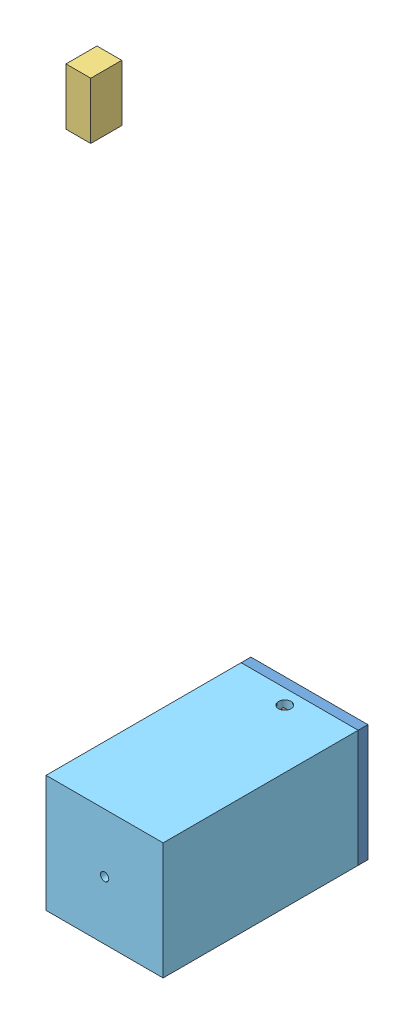
SolidWorks assembly Tongue assembly, configuration Default. Lengths in mm.
Overall size (482.24 379.28 414.44).
5 component instances, 5 part files, 9 mates.
Components (placement in the parent):
- Front plate-1: Front plate [Default] at (336.2892 -25.1944 124.8895) size (120 120 10)
- Tongue-1: Tongue [Default] at (336.2892 59.8056 131.8895) x (1 0 0) z (0 1 0) size (30 16.5 46)
- Solenoid-1: Solenoid [Default] at (-73.2537 296.0844 -68.6464) size (25.4 58 31.8)
- Part1-1: Part1 [Default] at (357.7174 122.6882 129.8895) size (40 65 4.5)
- Box-1: Box [Default] at (336.2892 34.8056 319.8895) x (1 0 0) z (0 -1 0) size (120 200 120)
Mates (geometry in assembly coordinates):
- Coincident1: coincident anti-aligned: plane of Front plate-1 through (276.2892 94.8056 129.8895) normal (0 0 1); plane of Tongue-1 through (336.2892 59.8056 129.8895) normal (0 0 -1)
- Coincident4: coincident anti-aligned: plane of Front plate-1 through (276.2892 94.8056 129.8895) normal (0 0 1); plane of Part1-1 through (357.7174 122.6882 129.8895) normal (0 0 -1)
- Concentric2: concentric anti-aligned: circle of Front plate-1; circle of Part1-1
- Concentric3: concentric anti-aligned: circle of Front plate-1; circle of Part1-1
- Coincident7: coincident anti-aligned: plane of Tongue-1 through (321.2892 44.8056 129.8895) normal (-1 0 0); plane of Part1-1 through (321.2892 49.8056 134.3895) normal (1 0 0)
- Concentric4: concentric anti-aligned: circle of Front plate-1; circle of Box-1
- Concentric5: concentric anti-aligned: circle of Front plate-1; circle of Box-1
- Coincident10: coincident anti-aligned: plane of Front plate-1 through (276.2892 94.8056 129.8895) normal (0 0 1); plane of Box-1 through (336.2892 34.8056 129.8895) normal (0 0 -1)
- Distance1: distance = 20 mm anti-aligned: plane of Tongue-1 through (321.2892 44.8056 129.8895) normal (0 -1 0); plane of Part1-1 through (321.2892 24.8056 134.3895) normal (0 1 0)
